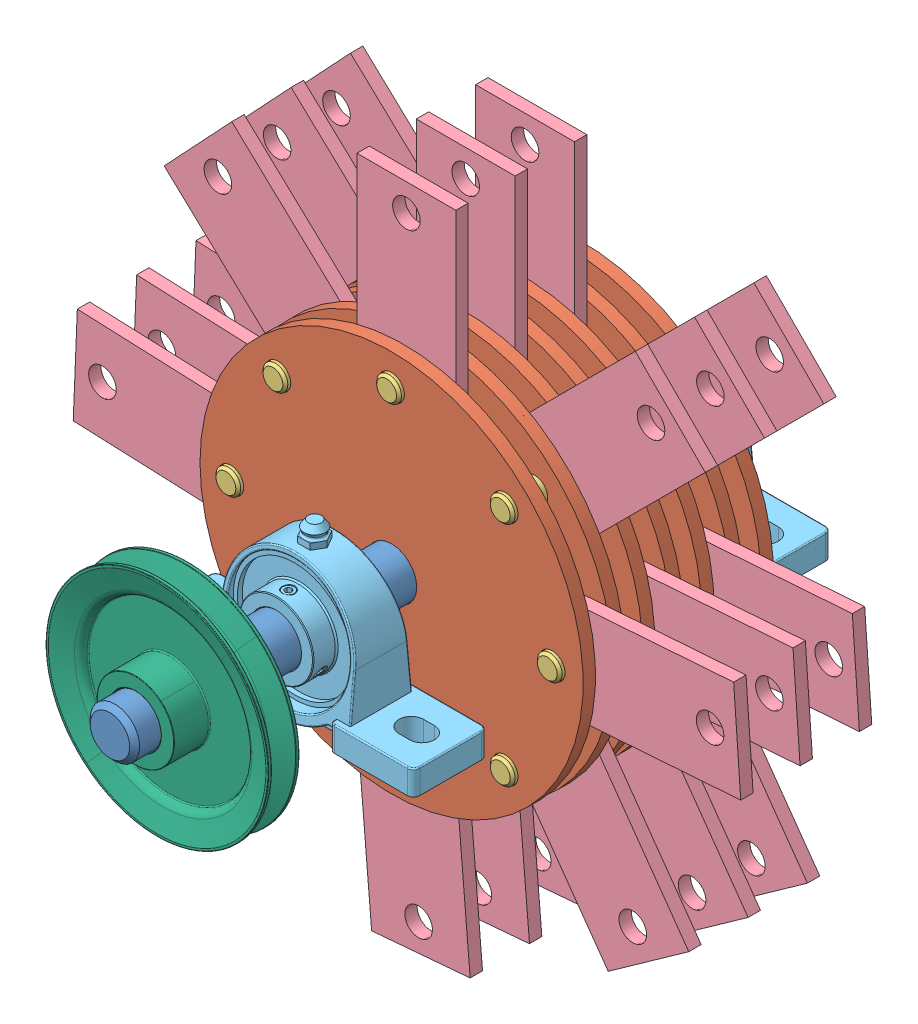
SolidWorks assembly Shaft Assembly, configuration Default. Lengths in mm.
Overall size (342.93 342.2 304.8).
51 component instances, 6 part files, 40 mates.
Components (placement in the parent):
- Shaft Assembly - Drive Shaft 0.75 in-1: Shaft Assembly - Drive Shaft 0.75 in [1346K31] at (114.0001 163.9812 230.4981) size (25.4 25.4 304.8)
- Shaft Assembly - Rotor Disc-1: Shaft Assembly - Rotor Disc [Default] at (114.0001 163.9812 140.4449) size (196.85 196.85 6.35)
- Shaft Assembly - Rotor Disc-2: Shaft Assembly - Rotor Disc [Default] at (114.0001 163.9812 155.6849) size (196.85 196.85 6.35)
- Shaft Assembly - Rotor Disc-3: Shaft Assembly - Rotor Disc [Default] at (114.0001 163.9812 170.9249) x (0.707107 -0.707107 0) z (0 0 1) size (196.85 196.85 6.35)
- Shaft Assembly - Rotor Disc-4: Shaft Assembly - Rotor Disc [Default] at (114.0001 163.9812 186.1649) size (196.85 196.85 6.35)
- Shaft Assembly - Rotor Disc-5: Shaft Assembly - Rotor Disc [Default] at (114.0001 163.9812 201.4049) size (196.85 196.85 6.35)
- Shaft Assembly - Rotor Disc-6: Shaft Assembly - Rotor Disc [Default] at (114.0001 163.9812 216.6449) size (196.85 196.85 6.35)
- Shaft Assembly - Rotor Disc-7: Shaft Assembly - Rotor Disc [Default] at (114.0001 163.9812 231.8849) size (196.85 196.85 6.35)
- Shaft Assembly - Hammer Subassembly-9: Shaft Assembly - Hammer Subassembly [Default] at (-2.1993 87.7165 -43.5077) size (50.8 101.6 102.87)
  - Shaft Assembly - Small Hammer Shaft-1: Shaft Assembly - Small Hammer Shaft [1346K11] at (116.1994 158.8147 232.8476) size (12.7 12.7 102.87)
  - Shaft Assembly - Hammer-2: Shaft Assembly - Hammer [Default] at (141.5994 144.8447 213.1626) x (-1 0 0) z (0 -1 0) size (50.8 6.35 101.6)
  - Shaft Assembly - Hammer-4: Shaft Assembly - Hammer [Default] at (141.5994 144.8447 274.1226) x (-1 0 0) z (0 -1 0) size (50.8 6.35 101.6)
  - Shaft Assembly - Hammer-5: Shaft Assembly - Hammer [Default] at (141.5994 144.8447 243.6426) x (-1 0 0) z (0 -1 0) size (50.8 6.35 101.6)
- Shaft Assembly - Hammer Subassembly-10: Shaft Assembly - Hammer Subassembly [Default] at (-14.3553 167.7177 422.1875) x (0.815022 0.57943 0) z (0 0 -1) size (50.8 101.6 102.87)
  - Shaft Assembly - Small Hammer Shaft-1: Shaft Assembly - Small Hammer Shaft [1346K11] at (116.1994 158.8147 232.8476) size (12.7 12.7 102.87)
  - Shaft Assembly - Hammer-2: Shaft Assembly - Hammer [Default] at (141.5994 144.8447 213.1626) x (-1 0 0) z (0 -1 0) size (50.8 6.35 101.6)
  - Shaft Assembly - Hammer-4: Shaft Assembly - Hammer [Default] at (141.5994 144.8447 274.1226) x (-1 0 0) z (0 -1 0) size (50.8 6.35 101.6)
  - Shaft Assembly - Hammer-5: Shaft Assembly - Hammer [Default] at (141.5994 144.8447 243.6426) x (-1 0 0) z (0 -1 0) size (50.8 6.35 101.6)
- Shaft Assembly - Hammer Subassembly-11: Shaft Assembly - Hammer Subassembly [Default] at (185.3268 41.3176 -43.5077) x (0.041328 0.999146 0) z (0 0 1) size (50.8 101.6 102.87)
  - Shaft Assembly - Small Hammer Shaft-1: Shaft Assembly - Small Hammer Shaft [1346K11] at (116.1994 158.8147 232.8476) size (12.7 12.7 102.87)
  - Shaft Assembly - Hammer-2: Shaft Assembly - Hammer [Default] at (141.5994 144.8447 213.1626) x (-1 0 0) z (0 -1 0) size (50.8 6.35 101.6)
  - Shaft Assembly - Hammer-4: Shaft Assembly - Hammer [Default] at (141.5994 144.8447 274.1226) x (-1 0 0) z (0 -1 0) size (50.8 6.35 101.6)
  - Shaft Assembly - Hammer-5: Shaft Assembly - Hammer [Default] at (141.5994 144.8447 243.6426) x (-1 0 0) z (0 -1 0) size (50.8 6.35 101.6)
- Shaft Assembly - Hammer Subassembly-12: Shaft Assembly - Hammer Subassembly [Default] at (142.2666 27.8842 422.1875) x (-0.70721 0.707003 0) z (0 0 -1) size (50.8 101.6 102.87)
  - Shaft Assembly - Small Hammer Shaft-1: Shaft Assembly - Small Hammer Shaft [1346K11] at (116.1994 158.8147 232.8476) size (12.7 12.7 102.87)
  - Shaft Assembly - Hammer-2: Shaft Assembly - Hammer [Default] at (141.5994 144.8447 213.1626) x (-1 0 0) z (0 -1 0) size (50.8 6.35 101.6)
  - Shaft Assembly - Hammer-4: Shaft Assembly - Hammer [Default] at (141.5994 144.8447 274.1226) x (-1 0 0) z (0 -1 0) size (50.8 6.35 101.6)
  - Shaft Assembly - Hammer-5: Shaft Assembly - Hammer [Default] at (141.5994 144.8447 243.6426) x (-1 0 0) z (0 -1 0) size (50.8 6.35 101.6)
- Shaft Assembly - Hammer Subassembly-13: Shaft Assembly - Hammer Subassembly [Default] at (29.8123 268.494 -43.5077) x (0.071703 -0.997426 0) z (0 0 1) size (50.8 101.6 102.87)
  - Shaft Assembly - Small Hammer Shaft-1: Shaft Assembly - Small Hammer Shaft [1346K11] at (116.1994 158.8147 232.8476) size (12.7 12.7 102.87)
  - Shaft Assembly - Hammer-2: Shaft Assembly - Hammer [Default] at (141.5994 144.8447 213.1626) x (-1 0 0) z (0 -1 0) size (50.8 6.35 101.6)
  - Shaft Assembly - Hammer-4: Shaft Assembly - Hammer [Default] at (141.5994 144.8447 274.1226) x (-1 0 0) z (0 -1 0) size (50.8 6.35 101.6)
  - Shaft Assembly - Hammer-5: Shaft Assembly - Hammer [Default] at (141.5994 144.8447 243.6426) x (-1 0 0) z (0 -1 0) size (50.8 6.35 101.6)
- Shaft Assembly - Hammer Subassembly-14: Shaft Assembly - Hammer Subassembly [Default] at (93.0072 298.8121 422.1875) x (0.680192 -0.733034 0) z (0 0 -1) size (50.8 101.6 102.87)
  - Shaft Assembly - Small Hammer Shaft-1: Shaft Assembly - Small Hammer Shaft [1346K11] at (116.1994 158.8147 232.8476) size (12.7 12.7 102.87)
  - Shaft Assembly - Hammer-2: Shaft Assembly - Hammer [Default] at (141.5994 144.8447 213.1626) x (-1 0 0) z (0 -1 0) size (50.8 6.35 101.6)
  - Shaft Assembly - Hammer-4: Shaft Assembly - Hammer [Default] at (141.5994 144.8447 274.1226) x (-1 0 0) z (0 -1 0) size (50.8 6.35 101.6)
  - Shaft Assembly - Hammer-5: Shaft Assembly - Hammer [Default] at (141.5994 144.8447 243.6426) x (-1 0 0) z (0 -1 0) size (50.8 6.35 101.6)
- Shaft Assembly - Hammer Subassembly-15: Shaft Assembly - Hammer Subassembly [Default] at (250.9644 198.5148 422.1875) x (-0.683903 -0.729573 0) z (0 0 -1) size (50.8 101.6 102.87)
  - Shaft Assembly - Small Hammer Shaft-1: Shaft Assembly - Small Hammer Shaft [1346K11] at (116.1994 158.8147 232.8476) size (12.7 12.7 102.87)
  - Shaft Assembly - Hammer-2: Shaft Assembly - Hammer [Default] at (141.5994 144.8447 213.1626) x (-1 0 0) z (0 -1 0) size (50.8 6.35 101.6)
  - Shaft Assembly - Hammer-4: Shaft Assembly - Hammer [Default] at (141.5994 144.8447 274.1226) x (-1 0 0) z (0 -1 0) size (50.8 6.35 101.6)
  - Shaft Assembly - Hammer-5: Shaft Assembly - Hammer [Default] at (141.5994 144.8447 243.6426) x (-1 0 0) z (0 -1 0) size (50.8 6.35 101.6)
- Shaft Assembly - Hammer Subassembly-16: Shaft Assembly - Hammer Subassembly [Default] at (216.2627 249.5585 -43.5077) x (-0.996372 -0.085101 0) z (0 0 1) size (50.8 101.6 102.87)
  - Shaft Assembly - Small Hammer Shaft-1: Shaft Assembly - Small Hammer Shaft [1346K11] at (116.1994 158.8147 232.8476) size (12.7 12.7 102.87)
  - Shaft Assembly - Hammer-2: Shaft Assembly - Hammer [Default] at (141.5994 144.8447 213.1626) x (-1 0 0) z (0 -1 0) size (50.8 6.35 101.6)
  - Shaft Assembly - Hammer-4: Shaft Assembly - Hammer [Default] at (141.5994 144.8447 274.1226) x (-1 0 0) z (0 -1 0) size (50.8 6.35 101.6)
  - Shaft Assembly - Hammer-5: Shaft Assembly - Hammer [Default] at (141.5994 144.8447 243.6426) x (-1 0 0) z (0 -1 0) size (50.8 6.35 101.6)
- Shaft Assembly - Bearing 1 in-1: Shaft Assembly - Bearing 1 in [6494K14] at (114.0001 163.9812 100.9581) x (-1 0 0) z (0 0 -1) size (139.7 80.17 38.89)
- Shaft Assembly - Bearing 1 in-2: Shaft Assembly - Bearing 1 in [6494K14] at (114.0001 163.9812 277.7218) size (139.7 80.17 38.89)
- Shaft Assembly - Pulley 1 in new-1: Shaft Assembly - Pulley 1 in new [Default] at (150.1141 166.8738 330.903) x (-0.761304 0.648395 0) z (0 0 1) size (114.3 114.3 27.17)
Mates (geometry in assembly coordinates):
- Concentric2: concentric aligned: cylinder of Shaft Assembly - Drive Shaft 0.75 in-1 through (114.0001 163.9812 382.8981) axis (0 0 -1) radius 12.7; cylinder of Shaft Assembly - Rotor Disc-1 through (114.0001 163.9812 146.7949) axis (0 0 -1) radius 12.954
- Parallel1: parallel aligned: line of Shaft Assembly - Drive Shaft 0.75 in-1 through (114.0001 176.6812 120.0081) axis (0 -1 0); line of Shaft Assembly - Rotor Disc-1 through (114.0001 262.4062 140.4449) axis (0 -1 0)
- Concentric4: concentric aligned: cylinder of Shaft Assembly - Drive Shaft 0.75 in-1 through (114.0001 163.9812 382.8981) axis (0 0 -1) radius 12.7; cylinder of Shaft Assembly - Rotor Disc-2 through (114.0001 163.9812 162.0349) axis (0 0 -1) radius 12.954
- Coincident6: coincident aligned: line of Shaft Assembly - Drive Shaft 0.75 in-1 through (114.0001 176.6812 155.6849) axis (0 -1 0); line of Shaft Assembly - Rotor Disc-2 through (114.0001 262.4062 155.6849) axis (0 -1 0)
- Concentric5: concentric aligned: cylinder of Shaft Assembly - Drive Shaft 0.75 in-1 through (114.0001 163.9812 382.8981) axis (0 0 -1) radius 12.7; cylinder of Shaft Assembly - Rotor Disc-3 through (114.0001 163.9812 177.2749) axis (0 0 -1) radius 12.954
- Coincident7: coincident: line of Shaft Assembly - Drive Shaft 0.75 in-1 through (114.0001 176.6812 170.9249) axis (0 -1 0); plane of Shaft Assembly - Rotor Disc-3 through (114.0001 163.9812 170.9249) normal (0 0 -1)
- Concentric6: concentric aligned: cylinder of Shaft Assembly - Drive Shaft 0.75 in-1 through (114.0001 163.9812 382.8981) axis (0 0 -1) radius 12.7; cylinder of Shaft Assembly - Rotor Disc-4 through (114.0001 163.9812 192.5149) axis (0 0 -1) radius 12.954
- Coincident8: coincident aligned: line of Shaft Assembly - Drive Shaft 0.75 in-1 through (114.0001 176.6812 186.1649) axis (0 -1 0); line of Shaft Assembly - Rotor Disc-4 through (114.0001 262.4062 186.1649) axis (0 -1 0)
- Coincident11: coincident aligned: line of Shaft Assembly - Drive Shaft 0.75 in-1 through (114.0001 176.6812 201.4049) axis (0 -1 0); line of Shaft Assembly - Rotor Disc-5 through (114.0001 262.4062 201.4049) axis (0 -1 0)
- Concentric7: concentric aligned: cylinder of Shaft Assembly - Drive Shaft 0.75 in-1 through (114.0001 163.9812 382.8981) axis (0 0 -1) radius 12.7; cylinder of Shaft Assembly - Rotor Disc-5 through (114.0001 163.9812 207.7549) axis (0 0 -1) radius 12.954
- Coincident12: coincident aligned: line of Shaft Assembly - Drive Shaft 0.75 in-1 through (114.0001 176.6812 216.6449) axis (0 -1 0); line of Shaft Assembly - Rotor Disc-6 through (114.0001 262.4062 216.6449) axis (0 -1 0)
- Concentric8: concentric aligned: cylinder of Shaft Assembly - Drive Shaft 0.75 in-1 through (114.0001 163.9812 382.8981) axis (0 0 -1) radius 12.7; cylinder of Shaft Assembly - Rotor Disc-6 through (114.0001 163.9812 222.9949) axis (0 0 -1) radius 12.954
- Coincident14: coincident aligned: line of Shaft Assembly - Drive Shaft 0.75 in-1 through (114.0001 176.6812 231.8849) axis (0 -1 0); line of Shaft Assembly - Rotor Disc-7 through (114.0001 262.4062 231.8849) axis (0 -1 0)
- Concentric9: concentric aligned: cylinder of Shaft Assembly - Drive Shaft 0.75 in-1 through (114.0001 163.9812 382.8981) axis (0 0 -1) radius 12.7; cylinder of Shaft Assembly - Rotor Disc-7 through (114.0001 163.9812 238.2349) axis (0 0 -1) radius 12.954
- Concentric10: concentric aligned: cylinder of Shaft Assembly - Rotor Disc-7 through (114.0001 246.5312 238.2349) axis (0 0 -1) radius 6.604; cylinder of Shaft Assembly - Hammer Subassembly-9/Shaft Assembly - Small Hammer Shaft-1 through (114.0001 246.5312 240.7749) axis (0 0 -1) radius 6.35
- Parallel2: parallel aligned: line of Shaft Assembly - Drive Shaft 0.75 in-1 through (114.0001 176.6812 258.6718) axis (0 -1 0); line of Shaft Assembly - Hammer Subassembly-9/Shaft Assembly - Hammer-4 through (139.4001 334.1612 230.6149) axis (0 -1 0)
- Concentric12: concentric anti-aligned: cylinder of Shaft Assembly - Rotor Disc-7 through (172.3718 222.3529 238.2349) axis (0 0 -1) radius 6.604; cylinder of Shaft Assembly - Hammer Subassembly-12/Shaft Assembly - Small Hammer Shaft-1 through (172.3718 222.3529 137.9049) axis (0 0 1) radius 6.35
- Coincident17: coincident: plane of Shaft Assembly - Rotor Disc-1 through (114.0001 163.9812 140.4449) normal (0 0 -1); point of Shaft Assembly - Hammer Subassembly-12/Shaft Assembly - Small Hammer Shaft-1
- Concentric13: concentric aligned: cylinder of Shaft Assembly - Rotor Disc-7 through (196.5501 163.9812 238.2349) axis (0 0 -1) radius 6.604; cylinder of Shaft Assembly - Hammer Subassembly-13/Shaft Assembly - Small Hammer Shaft-1 through (196.5501 163.9812 240.7749) axis (0 0 -1) radius 6.35
- Coincident18: coincident: plane of Shaft Assembly - Rotor Disc-7 through (114.0001 163.9812 238.2349) normal (0 0 1)
- Concentric14: concentric anti-aligned: cylinder of Shaft Assembly - Rotor Disc-7 through (172.3718 105.6096 238.2349) axis (0 0 -1) radius 6.604; cylinder of Shaft Assembly - Hammer Subassembly-10/Shaft Assembly - Small Hammer Shaft-1 through (172.3718 105.6096 137.9049) axis (0 0 1) radius 6.35
- Coincident19: coincident: plane of Shaft Assembly - Rotor Disc-1 through (114.0001 163.9812 140.4449) normal (0 0 -1)
- Concentric15: concentric aligned: cylinder of Shaft Assembly - Rotor Disc-7 through (114.0001 81.4312 238.2349) axis (0 0 -1) radius 6.604; cylinder of Shaft Assembly - Hammer Subassembly-16/Shaft Assembly - Small Hammer Shaft-1 through (114.0001 81.4312 240.7749) axis (0 0 -1) radius 6.35
- Coincident20: coincident: plane of Shaft Assembly - Rotor Disc-7 through (114.0001 163.9812 238.2349) normal (0 0 1)
- Concentric16: concentric anti-aligned: cylinder of Shaft Assembly - Rotor Disc-7 through (55.6284 105.6096 238.2349) axis (0 0 -1) radius 6.604; cylinder of Shaft Assembly - Hammer Subassembly-14/Shaft Assembly - Small Hammer Shaft-1 through (55.6284 105.6096 137.9049) axis (0 0 1) radius 6.35
- Coincident21: coincident: plane of Shaft Assembly - Rotor Disc-1 through (114.0001 163.9812 140.4449) normal (0 0 -1)
- Concentric17: concentric aligned: cylinder of Shaft Assembly - Rotor Disc-7 through (31.4501 163.9812 238.2349) axis (0 0 -1) radius 6.604; cylinder of Shaft Assembly - Hammer Subassembly-11/Shaft Assembly - Small Hammer Shaft-1 through (31.4501 163.9812 240.7749) axis (0 0 -1) radius 6.35
- Coincident22: coincident: plane of Shaft Assembly - Rotor Disc-7 through (114.0001 163.9812 238.2349) normal (0 0 1)
- Concentric18: concentric anti-aligned: cylinder of Shaft Assembly - Rotor Disc-7 through (55.6284 222.3529 238.2349) axis (0 0 -1) radius 6.604; cylinder of Shaft Assembly - Hammer Subassembly-15/Shaft Assembly - Small Hammer Shaft-1 through (55.6284 222.3529 137.9049) axis (0 0 1) radius 6.35
- Coincident23: coincident: plane of Shaft Assembly - Rotor Disc-1 through (114.0001 163.9812 140.4449) normal (0 0 -1)
- Concentric19: concentric aligned: cylinder of Shaft Assembly - Drive Shaft 0.75 in-1 through (114.0001 163.9812 382.8981) axis (0 0 -1) radius 12.7; cylinder of Shaft Assembly - Bearing 1 in-1 through (114.0001 163.9812 115.2456) axis (0 0 -1) radius 12.7
- Parallel3: parallel aligned: line of Shaft Assembly - Drive Shaft 0.75 in-1 through (114.0001 176.6812 120.0081) axis (0 -1 0); line of Shaft Assembly - Bearing 1 in-1 through (183.8501 139.5337 116.8331) axis (0 -1 0)
- Coincident25: coincident: line of Shaft Assembly - Drive Shaft 0.75 in-1 through (114.0001 176.6812 120.0081) axis (0 -1 0); plane of Shaft Assembly - Bearing 1 in-1 through (114.0001 163.9812 120.0081) normal (0 0 1)
- Concentric20: concentric anti-aligned: cylinder of Shaft Assembly - Drive Shaft 0.75 in-1 through (114.0001 163.9812 382.8981) axis (0 0 -1) radius 12.7; cylinder of Shaft Assembly - Bearing 1 in-2 through (114.0001 163.9812 263.4343) axis (0 0 1) radius 12.7
- Parallel4: parallel anti-aligned: line of Shaft Assembly - Drive Shaft 0.75 in-1 through (114.0001 176.6812 258.6718) axis (0 -1 0); line of Shaft Assembly - Bearing 1 in-2 through (183.8501 127.4687 261.8468) axis (0 1 0)
- Coincident27: coincident: line of Shaft Assembly - Drive Shaft 0.75 in-1 through (114.0001 176.6812 258.6718) axis (0 -1 0); plane of Shaft Assembly - Bearing 1 in-2 through (114.0001 163.9812 258.6718) normal (0 0 -1)
- Coincident29: coincident: plane of Shaft Assembly - Rotor Disc-7 through (114.0001 163.9812 238.2349) normal (0 0 1)
- Coincident30: coincident: line of Shaft Assembly - Drive Shaft 0.75 in-1 through (114.0001 176.6812 347.5718) axis (0 -1 0); plane of Shaft Assembly - Pulley 1 in new-1 through (114.0001 163.9812 347.5718) normal (0 0 -1)
- Coincident31: coincident: line of Shaft Assembly - Drive Shaft 0.75 in-1 through (114.0001 176.6812 140.4449) axis (0 -1 0); plane of Shaft Assembly - Rotor Disc-1 through (114.0001 163.9812 140.4449) normal (0 0 -1)
- Concentric23: concentric aligned: cylinder of Shaft Assembly - Drive Shaft 0.75 in-1 through (114.0001 163.9812 382.8981) axis (0 0 -1) radius 12.7; cylinder of Shaft Assembly - Pulley 1 in new-1 through (114.0001 163.9812 435.678) axis (0 0 -1) radius 12.7
